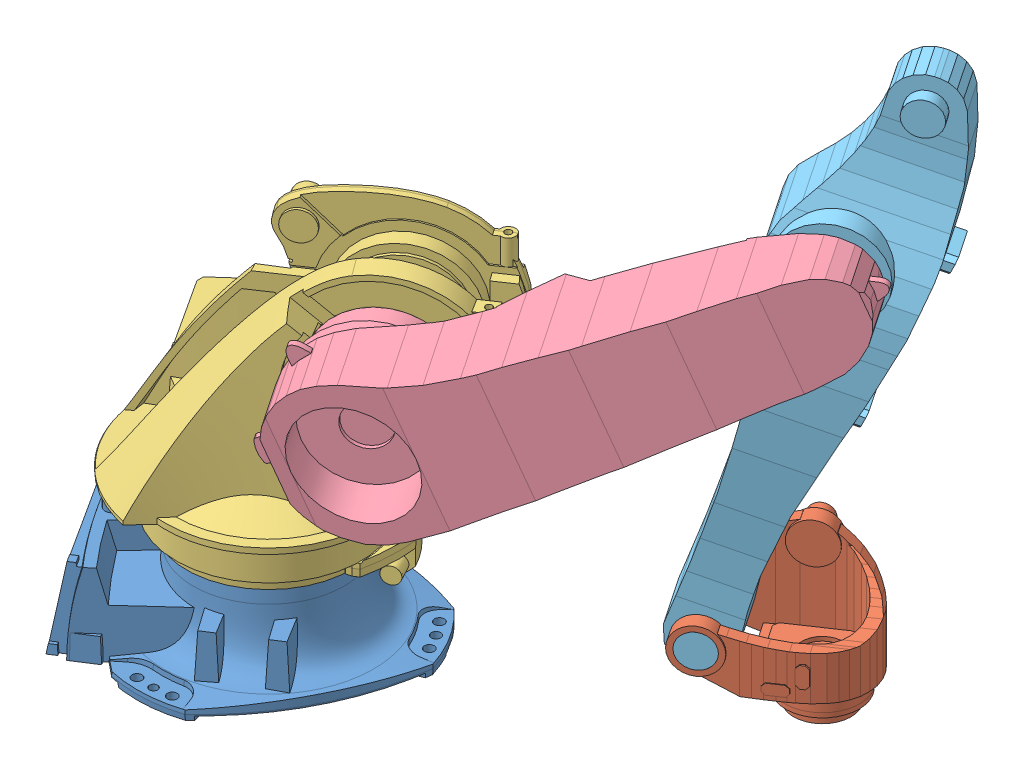
SolidWorks assembly AssemTest, configuration Default. Lengths in mm.
Overall size (1693.44 1421.1 1279.01).
5 component instances, 5 part files, 8 mates.
Components (placement in the parent):
- Part1-1: Part1 [Default] at (-849.1772 -745.4546 -257.122) x (0.541164 0 0.840917) z (0 1 0) size (629.29 670.6 298.5)
- Part10-1: Part10 [Default] at (-138.0197 -617.4571 -619.3937) x (0.828866 0 -0.559447) z (-0.559447 0 -0.828866) size (362.73 333.52 278)
- Part2-1: Part2 [Default] at (-595.8433 -125.4546 -311.5902) x (0.828866 0 -0.559447) z (-0.559447 0 -0.828866) size (813.53 742.49 651.71)
- Part3-1: Part3 [Default] at (55.6305 199.804 -750.0987) x (0.765782 0.382657 -0.516867) z (-0.559447 0 -0.828866) size (1188.3 385.45 331.01)
- Part9-1: Part9 [Default] at (-138.0197 -617.4571 -619.3937) x (-0.227824 -0.961484 0.153771) z (-0.559447 0 -0.828866) size (1331.58 323.8 230)
Mates (geometry in assembly coordinates):
- Coincident1: coincident aligned: cylinder of Part1-1 through (-837.775 -535.4546 -276.7862) axis (0 -1 0) radius 50; circle of Part2-1
- Coincident2: coincident anti-aligned: plane of Part1-1 through (-837.775 -545.4546 -276.7862) normal (0 1 0); plane of Part2-1 through (-837.775 -545.4546 -276.7862) normal (0 -1 0)
- Concentric1: concentric aligned: circle of Part2-1; circle of Part3-1
- Coincident3: coincident anti-aligned: plane of Part2-1 through (-614.8645 -125.4546 -339.7716) normal (0.559447 0 0.828866); plane of Part3-1 through (-614.8645 -125.4546 -339.7716) normal (-0.559447 0 -0.828866)
- Concentric2: concentric aligned: circle of Part3-1; circle of Part9-1
- Coincident4: coincident anti-aligned: plane of Part3-1 through (50.036 199.804 -758.3873) normal (-0.559447 0 -0.828866); plane of Part9-1 through (50.036 199.804 -758.3873) normal (0.559447 0 0.828866)
- Concentric3: concentric aligned: circle of Part10-1; circle of Part9-1
- Coincident5: coincident aligned: plane of Part10-1 through (-133.8238 -617.4571 -613.1772) normal (0.559447 0 0.828866); plane of Part9-1 through (-133.8238 -617.4571 -613.1772) normal (0.559447 0 0.828866)
